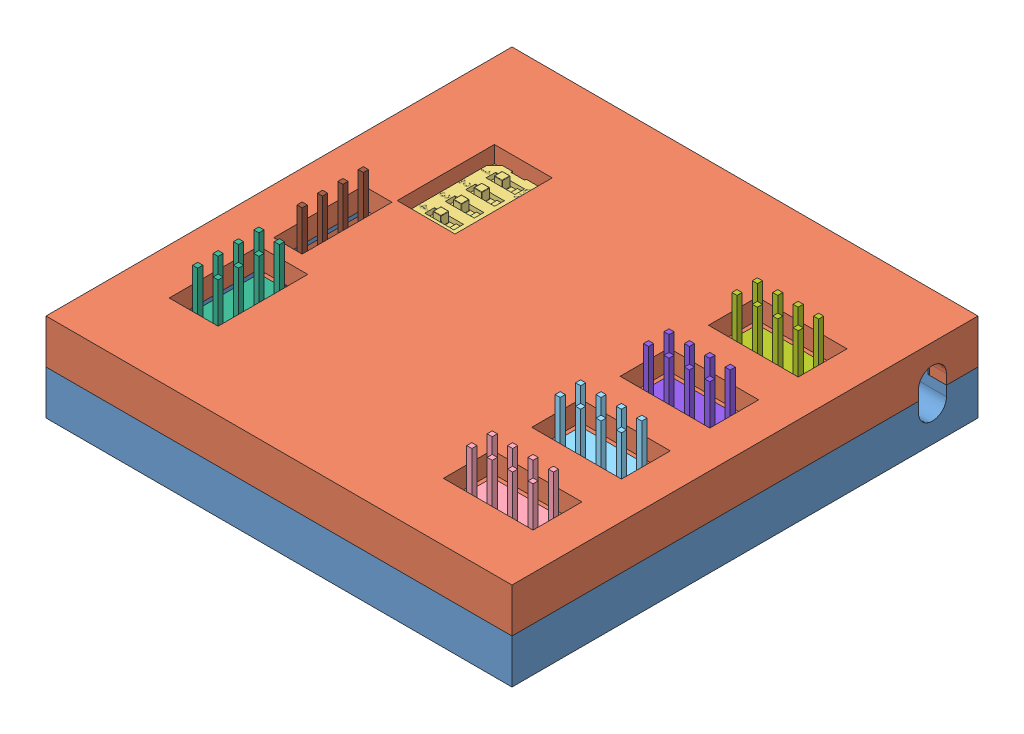
SolidWorks assembly batman, configuration 默认. Lengths in mm.
Overall size (58 14.53 58).
199 component instances, 74 part files, 6 mates.
Components (placement in the parent):
- base-2: base [默认] at (12.8694 5.5 -3.2255) size (58 8.5 58)
- PCB1-1: PCB1 [默认] at (-12.1306 5.9914 21.7745) x (1 0 0) z (0 1 0) size (50 50 11.54)
  - PCB1(2)^PCB1-1: PCB1(2)^PCB1 [默认] at origin size (50 50 11.54) (virtual)
    - Boardbat^PCB1(2)_PCB1-1: Boardbat^PCB1(2)_PCB1 [默认] at origin size (50 50 1.69) (virtual)
      - Open CASCADE STEP translator 6.8 2.1.1^Boardbat_PCB1(2)_PCB1-1: Open CASCADE STEP translator 6.8 2.1.1^Boardbat_PCB1(2)_PCB1 [默认] at (0 0 -1.6914) size (50 50 1.69) (virtual)
    - S1bat^PCB1(2)_PCB1-1: S1bat^PCB1(2)_PCB1 [默认] at origin size (9.8 11.1 4.34) (virtual)
      - SMD_DIP_SWITCH_4P^S1bat_PCB1(2)_PCB1-1: SMD_DIP_SWITCH_4P^S1bat_PCB1(2)_PCB1 [默认] at (9.0244 36.3424 0) x (0 -1 0) z (0 0 1) size (11.1 9.8 4.34) (virtual)
    - P6bat^PCB1(2)_PCB1-1: P6bat^PCB1(2)_PCB1 [默认] at origin size (10.16 5.08 11.54) (virtual)
      - HDR2x4^P6bat_PCB1(2)_PCB1-1: HDR2x4^P6bat_PCB1(2)_PCB1 [默认] at (40.0001 7.5401 0) x (1 0 0) z (0 0 1) size (10.16 5.08 11.54) (virtual)
    - P5bat^PCB1(2)_PCB1-1: P5bat^PCB1(2)_PCB1 [默认] at origin size (10.16 5.08 11.54) (virtual)
      - HDR2x4^P5bat_PCB1(2)_PCB1-1: HDR2x4^P5bat_PCB1(2)_PCB1 [默认] at (40.0001 18.5401 0) x (1 0 0) z (0 0 1) size (10.16 5.08 11.54) (virtual)
    - P4bat^PCB1(2)_PCB1-1: P4bat^PCB1(2)_PCB1 [默认] at origin size (5.08 10.16 11.54) (virtual)
      - HDR2x4^P4bat_PCB1(2)_PCB1-1: HDR2x4^P4bat_PCB1(2)_PCB1 [默认] at (6.0401 14.9999 0) x (0 -1 0) z (0 0 1) size (10.16 5.08 11.54) (virtual)
    - P3bat^PCB1(2)_PCB1-1: P3bat^PCB1(2)_PCB1 [默认] at origin size (10.16 5.08 11.54) (virtual)
      - HDR2x4^P3bat_PCB1(2)_PCB1-1: HDR2x4^P3bat_PCB1(2)_PCB1 [默认] at (40.0001 40.5401 0) x (1 0 0) z (0 0 1) size (10.16 5.08 11.54) (virtual)
    - P2bat^PCB1(2)_PCB1-1: P2bat^PCB1(2)_PCB1 [默认] at origin size (10.16 5.08 11.54) (virtual)
      - HDR2x4^P2bat_PCB1(2)_PCB1-1: HDR2x4^P2bat_PCB1(2)_PCB1 [默认] at (40.0001 29.5401 0) x (1 0 0) z (0 0 1) size (10.16 5.08 11.54) (virtual)
    - U3bat^PCB1(2)_PCB1-1: U3bat^PCB1(2)_PCB1 [默认] at origin size (2.8 2.9 1.45) (virtual)
      - 6249525824^U3bat_PCB1(2)_PCB1-1: 6249525824^U3bat_PCB1(2)_PCB1 [默认] at (16.256 4.064 0) x (-1 0 0) z (0 0 1) size (2.8 2.9 1.45) (virtual)
        - Body^6249525824_U3bat_PCB1(2)_PCB1-1: Body^6249525824_U3bat_PCB1(2)_PCB1 [默认] at origin size (1.6 2.9 1.38) (virtual)
        - PinsArrayLR^6249525824_U3bat_PCB1(2)_PCB1-1: PinsArrayLR^6249525824_U3bat_PCB1(2)_PCB1 [默认] at origin size (2.8 2.3 0.75) (virtual)
    - U2bat^PCB1(2)_PCB1-1: U2bat^PCB1(2)_PCB1 [默认] at origin size (2.9 2.8 1) (virtual)
      - 6249527824^U2bat_PCB1(2)_PCB1-1: 6249527824^U2bat_PCB1(2)_PCB1 [默认] at (22.987 15.509 0) x (0 -1 0) z (-1 0 0) size (2.8 1 2.9) (virtual)
    - U1bat^PCB1(2)_PCB1-1: U1bat^PCB1(2)_PCB1 [默认] at origin size (2.9 2.8 1) (virtual)
      - 6249527824^U1bat_PCB1(2)_PCB1-1: 6249527824^U1bat_PCB1(2)_PCB1 [默认] at (25.527 40.075 0) x (0 -1 0) z (-1 0 0) size (2.8 1 2.9) (virtual)
    - R15bat^PCB1(2)_PCB1-1: R15bat^PCB1(2)_PCB1 [默认] at origin size (1.6 0.8 0.45) (virtual)
      - R0603^R15bat_PCB1(2)_PCB1-1: R0603^R15bat_PCB1(2)_PCB1 [默认] at (21.7171 8.6361 0) x (1 0 0) z (0 0 1) size (1.6 0.8 0.45) (virtual)
    - R14bat^PCB1(2)_PCB1-1: R14bat^PCB1(2)_PCB1 [默认] at origin size (3.46 3.05 1.58) (virtual)
      - 6249526064^R14bat_PCB1(2)_PCB1-1: 6249526064^R14bat_PCB1(2)_PCB1 [默认] at (29.718 7.62 4.4704) x (0 -1 0) z (0 0 -1) size (3.05 3.46 1.58) (virtual)
        - pot1.1^6249526064_R14bat_PCB1(2)_PCB1-1: pot1.1^6249526064_R14bat_PCB1(2)_PCB1 [默认] at (-1.7102 -1.6618 3.4563) size (3 3.46 1.06) (virtual)
        - pot.2^6249526064_R14bat_PCB1(2)_PCB1-1: pot.2^6249526064_R14bat_PCB1(2)_PCB1 [默认] at (-0.2427 -0.0677 2.935) x (-0.009438 0.999936 -0.006241) z (-0.002294 0.00622 0.999978) size (3.06 3 0.7) (virtual)
    - R13bat^PCB1(2)_PCB1-1: R13bat^PCB1(2)_PCB1 [默认] at origin size (0.8 1.6 0.45) (virtual)
      - R0603^R13bat_PCB1(2)_PCB1-1: R0603^R13bat_PCB1(2)_PCB1 [默认] at (15.1131 8.3819 0) x (0 -1 0) z (0 0 1) size (1.6 0.8 0.45) (virtual)
    - R12bat^PCB1(2)_PCB1-1: R12bat^PCB1(2)_PCB1 [默认] at origin size (1.6 0.8 0.45) (virtual)
      - R0603^R12bat_PCB1(2)_PCB1-1: R0603^R12bat_PCB1(2)_PCB1 [默认] at (42.0369 2.4131 -1.6914) x (-1 0 0) z (0 0 -1) size (1.6 0.8 0.45) (virtual)
    - R11bat^PCB1(2)_PCB1-1: R11bat^PCB1(2)_PCB1 [默认] at origin size (0.8 1.6 0.45) (virtual)
      - R0603^R11bat_PCB1(2)_PCB1-1: R0603^R11bat_PCB1(2)_PCB1 [默认] at (33.9091 7.7469 0) x (0 -1 0) z (0 0 1) size (1.6 0.8 0.45) (virtual)
    - R10bat^PCB1(2)_PCB1-1: R10bat^PCB1(2)_PCB1 [默认] at origin size (1.6 0.8 0.45) (virtual)
      - R0603^R10bat_PCB1(2)_PCB1-1: R0603^R10bat_PCB1(2)_PCB1 [默认] at (18.6689 16.1289 0) x (-1 0 0) z (0 0 1) size (1.6 0.8 0.45) (virtual)
    - R9bat^PCB1(2)_PCB1-1: R9bat^PCB1(2)_PCB1 [默认] at origin size (1.6 0.8 0.45) (virtual)
      - R0603^R9bat_PCB1(2)_PCB1-1: R0603^R9bat_PCB1(2)_PCB1 [默认] at (42.0369 13.4621 -1.6914) x (-1 0 0) z (0 0 -1) size (1.6 0.8 0.45) (virtual)
    - R8bat^PCB1(2)_PCB1-1: R8bat^PCB1(2)_PCB1 [默认] at origin size (1.6 0.8 0.45) (virtual)
      - R0603^R8bat_PCB1(2)_PCB1-1: R0603^R8bat_PCB1(2)_PCB1 [默认] at (27.4321 13.8431 0) x (1 0 0) z (0 0 1) size (1.6 0.8 0.45) (virtual)
    - R7bat^PCB1(2)_PCB1-1: R7bat^PCB1(2)_PCB1 [默认] at origin size (1.6 0.8 0.45) (virtual)
      - R0603^R7bat_PCB1(2)_PCB1-1: R0603^R7bat_PCB1(2)_PCB1 [默认] at (18.6689 13.9699 0) x (-1 0 0) z (0 0 1) size (1.6 0.8 0.45) (virtual)
    - R6bat^PCB1(2)_PCB1-1: R6bat^PCB1(2)_PCB1 [默认] at origin size (0.8 1.6 0.45) (virtual)
      - R0603^R6bat_PCB1(2)_PCB1-1: R0603^R6bat_PCB1(2)_PCB1 [默认] at (17.6531 19.5579 0) x (0 -1 0) z (0 0 1) size (1.6 0.8 0.45) (virtual)
    - R5bat^PCB1(2)_PCB1-1: R5bat^PCB1(2)_PCB1 [默认] at origin size (1.6 0.8 0.45) (virtual)
      - R0603^R5bat_PCB1(2)_PCB1-1: R0603^R5bat_PCB1(2)_PCB1 [默认] at (42.0371 24.3839 -1.6914) x (1 0 0) z (0 0 -1) size (1.6 0.8 0.45) (virtual)
    - R4bat^PCB1(2)_PCB1-1: R4bat^PCB1(2)_PCB1 [默认] at origin size (0.8 1.6 0.45) (virtual)
      - R0603^R4bat_PCB1(2)_PCB1-1: R0603^R4bat_PCB1(2)_PCB1 [默认] at (21.5899 39.1161 0) x (0 1 0) z (0 0 1) size (1.6 0.8 0.45) (virtual)
    - R3bat^PCB1(2)_PCB1-1: R3bat^PCB1(2)_PCB1 [默认] at origin size (1.6 0.8 0.45) (virtual)
      - R0603^R3bat_PCB1(2)_PCB1-1: R0603^R3bat_PCB1(2)_PCB1 [默认] at (41.9099 35.4331 -1.6914) x (-1 0 0) z (0 0 -1) size (1.6 0.8 0.45) (virtual)
    - R2bat^PCB1(2)_PCB1-1: R2bat^PCB1(2)_PCB1 [默认] at origin size (1.6 0.8 0.45) (virtual)
      - R0603^R2bat_PCB1(2)_PCB1-1: R0603^R2bat_PCB1(2)_PCB1 [默认] at (29.7181 38.7351 0) x (1 0 0) z (0 0 1) size (1.6 0.8 0.45) (virtual)
    - R1bat^PCB1(2)_PCB1-1: R1bat^PCB1(2)_PCB1 [默认] at origin size (0.8 1.6 0.45) (virtual)
      - R0603^R1bat_PCB1(2)_PCB1-1: R0603^R1bat_PCB1(2)_PCB1 [默认] at (21.7171 44.4499 0) x (0 -1 0) z (0 0 1) size (1.6 0.8 0.45) (virtual)
    - P1bat^PCB1(2)_PCB1-1: P1bat^PCB1(2)_PCB1 [默认] at origin size (2.54 10.16 11.54) (virtual)
      - 1001-4^P1bat_PCB1(2)_PCB1-1: 1001-4^P1bat_PCB1(2)_PCB1 [默认] at (3.5001 27.9999 0) x (0 -1 0) z (0 0 1) size (10.16 2.54 11.54) (virtual)
    - LED4bat^PCB1(2)_PCB1-1: LED4bat^PCB1(2)_PCB1 [默认] at origin size (1.8 0.9 0.8) (virtual)
      - LEDC0603^LED4bat_PCB1(2)_PCB1-1: LEDC0603^LED4bat_PCB1(2)_PCB1 [默认] at (43.9422 2.4131 0) x (1 0 0) z (0 0 1) size (1.8 0.9 0.8) (virtual)
    - LED3bat^PCB1(2)_PCB1-1: LED3bat^PCB1(2)_PCB1 [默认] at origin size (1.8 0.9 0.8) (virtual)
      - LEDC0603^LED3bat_PCB1(2)_PCB1-1: LEDC0603^LED3bat_PCB1(2)_PCB1 [默认] at (43.9422 13.4621 0) x (1 0 0) z (0 0 1) size (1.8 0.9 0.8) (virtual)
    - LED2bat^PCB1(2)_PCB1-1: LED2bat^PCB1(2)_PCB1 [默认] at origin size (1.8 0.9 0.8) (virtual)
      - LEDC0603^LED2bat_PCB1(2)_PCB1-1: LEDC0603^LED2bat_PCB1(2)_PCB1 [默认] at (43.8152 35.4331 0) x (1 0 0) z (0 0 1) size (1.8 0.9 0.8) (virtual)
    - LED1bat^PCB1(2)_PCB1-1: LED1bat^PCB1(2)_PCB1 [默认] at origin size (1.8 0.9 0.8) (virtual)
      - LEDC0603^LED1bat_PCB1(2)_PCB1-1: LEDC0603^LED1bat_PCB1(2)_PCB1 [默认] at (43.9422 24.3841 0) x (1 0 0) z (0 0 1) size (1.8 0.9 0.8) (virtual)
    - L3bat^PCB1(2)_PCB1-1: L3bat^PCB1(2)_PCB1 [默认] at origin size (4.2 4.7 1.85) (virtual)
      - CSAB0420^L3bat_PCB1(2)_PCB1-1: CSAB0420^L3bat_PCB1(2)_PCB1 [默认] at (22.479 3.5744 0.05) x (1 0 0) z (0 0 1) size (4.2 4.7 1.85) (virtual)
        - CSAB0420-0^CSAB0420_L3bat_PCB1(2)_PCB1-1: CSAB0420-0^CSAB0420_L3bat_PCB1(2)_PCB1 [默认] x (1 0 0) z (0 0 -1) size (4.2 4.2 1.8) (virtual)
        - 0420____^CSAB0420_L3bat_PCB1(2)_PCB1-1: 0420____^CSAB0420_L3bat_PCB1(2)_PCB1 [默认] at (0 -2.1 0.425) x (1 0 0) z (0 -1 0) size (2 1.2 0.95) (virtual)
        - 0420____^CSAB0420_L3bat_PCB1(2)_PCB1-2: 0420____^CSAB0420_L3bat_PCB1(2)_PCB1 [默认] at (0 2.1 0.425) x (-1 0 0) z (0 1 0) size (2 1.2 0.95) (virtual)
    - L2bat^PCB1(2)_PCB1-1: L2bat^PCB1(2)_PCB1 [默认] at origin size (4.2 4.7 1.85) (virtual)
      - CSAB0420^L2bat_PCB1(2)_PCB1-1: CSAB0420^L2bat_PCB1(2)_PCB1 [默认] at (30.353 19.9206 0.05) x (-1 0 0) z (0 0 1) size (4.2 4.7 1.85) (virtual)
        - CSAB0420-0^CSAB0420_L2bat_PCB1(2)_PCB1-1: CSAB0420-0^CSAB0420_L2bat_PCB1(2)_PCB1 [默认] x (1 0 0) z (0 0 -1) size (4.2 4.2 1.8) (virtual)
        - 0420____^CSAB0420_L2bat_PCB1(2)_PCB1-1: 0420____^CSAB0420_L2bat_PCB1(2)_PCB1 [默认] at (0 -2.1 0.425) x (1 0 0) z (0 -1 0) size (2 1.2 0.95) (virtual)
        - 0420____^CSAB0420_L2bat_PCB1(2)_PCB1-2: 0420____^CSAB0420_L2bat_PCB1(2)_PCB1 [默认] at (0 2.1 0.425) x (-1 0 0) z (0 1 0) size (2 1.2 0.95) (virtual)
    - L1bat^PCB1(2)_PCB1-1: L1bat^PCB1(2)_PCB1 [默认] at origin size (4.2 4.7 1.85) (virtual)
      - CSAB0420^L1bat_PCB1(2)_PCB1-1: CSAB0420^L1bat_PCB1(2)_PCB1 [默认] at (33.655 44.5586 0.05) x (-1 0 0) z (0 0 1) size (4.2 4.7 1.85) (virtual)
        - CSAB0420-0^CSAB0420_L1bat_PCB1(2)_PCB1-1: CSAB0420-0^CSAB0420_L1bat_PCB1(2)_PCB1 [默认] x (1 0 0) z (0 0 -1) size (4.2 4.2 1.8) (virtual)
        - 0420____^CSAB0420_L1bat_PCB1(2)_PCB1-1: 0420____^CSAB0420_L1bat_PCB1(2)_PCB1 [默认] at (0 -2.1 0.425) x (1 0 0) z (0 -1 0) size (2 1.2 0.95) (virtual)
        - 0420____^CSAB0420_L1bat_PCB1(2)_PCB1-2: 0420____^CSAB0420_L1bat_PCB1(2)_PCB1 [默认] at (0 2.1 0.425) x (-1 0 0) z (0 1 0) size (2 1.2 0.95) (virtual)
    - IC1bat^PCB1(2)_PCB1-1: IC1bat^PCB1(2)_PCB1 [默认] at origin size (6.71 6.3 1.8) (virtual)
      - 6249526864^IC1bat_PCB1(2)_PCB1-1: 6249526864^IC1bat_PCB1(2)_PCB1 [默认] at (24.257 29.845 1.22) x (0 1 0) z (1 0 0) size (6.3 1.8 6.71) (virtual)
    - D1bat^PCB1(2)_PCB1-1: D1bat^PCB1(2)_PCB1 [默认] at origin size (5.81 2.92 2.3) (virtual)
      - SMA(DO-214AC)^D1bat_PCB1(2)_PCB1-1: SMA(DO-214AC)^D1bat_PCB1(2)_PCB1 [默认] at (30.2261 3.0481 0) x (1 0 0) z (0 0 1) size (5.81 2.92 2.3) (virtual)
    - C16bat^PCB1(2)_PCB1-1: C16bat^PCB1(2)_PCB1 [默认] at origin size (0.95 1.75 0.85) (virtual)
      - 6351899600^C16bat_PCB1(2)_PCB1-1: 6351899600^C16bat_PCB1(2)_PCB1 [默认] at (17.145 8.382 0) size (0.95 1.05 0.85) (virtual)
        - Extruded^6351899600_C16bat_PCB1(2)_PCB1-1: Extruded^6351899600_C16bat_PCB1(2)_PCB1 [默认] at origin size (0.95 1.05 0.85) (virtual)
      - 6351899200^C16bat_PCB1(2)_PCB1-1: 6351899200^C16bat_PCB1(2)_PCB1 [默认] at (17.145 9.082 0) size (0.95 0.35 0.85) (virtual)
        - Extruded-1^6351899200_C16bat_PCB1(2)_PCB1-1: Extruded-1^6351899200_C16bat_PCB1(2)_PCB1 [默认] at origin size (0.95 0.35 0.85) (virtual)
      - 6351899200^C16bat_PCB1(2)_PCB1-2: 6351899200^C16bat_PCB1(2)_PCB1 [默认] at (17.145 7.682 0) size (0.95 0.35 0.85) (virtual)
        - Extruded-1^6351899200_C16bat_PCB1(2)_PCB1-1: Extruded-1^6351899200_C16bat_PCB1(2)_PCB1 [默认] at origin size (0.95 0.35 0.85) (virtual)
    - C15bat^PCB1(2)_PCB1-1: C15bat^PCB1(2)_PCB1 [默认] at origin size (0.95 1.75 0.85) (virtual)
      - 6351899200^C15bat_PCB1(2)_PCB1-1: 6351899200^C15bat_PCB1(2)_PCB1 [默认] at (35.941 4.764 0) size (0.95 0.35 0.85) (virtual)
        - Extruded-1^6351899200_C15bat_PCB1(2)_PCB1-1: Extruded-1^6351899200_C15bat_PCB1(2)_PCB1 [默认] at origin size (0.95 0.35 0.85) (virtual)
      - 6351899200^C15bat_PCB1(2)_PCB1-2: 6351899200^C15bat_PCB1(2)_PCB1 [默认] at (35.941 3.364 0) size (0.95 0.35 0.85) (virtual)
        - Extruded-1^6351899200_C15bat_PCB1(2)_PCB1-1: Extruded-1^6351899200_C15bat_PCB1(2)_PCB1 [默认] at origin size (0.95 0.35 0.85) (virtual)
      - 6351899600^C15bat_PCB1(2)_PCB1-1: 6351899600^C15bat_PCB1(2)_PCB1 [默认] at (35.941 4.064 0) size (0.95 1.05 0.85) (virtual)
        - Extruded^6351899600_C15bat_PCB1(2)_PCB1-1: Extruded^6351899600_C15bat_PCB1(2)_PCB1 [默认] at origin size (0.95 1.05 0.85) (virtual)
    - C14bat^PCB1(2)_PCB1-1: C14bat^PCB1(2)_PCB1 [默认] at origin size (1.75 0.95 0.85) (virtual)
      - 6351616128^C14bat_PCB1(2)_PCB1-1: 6351616128^C14bat_PCB1(2)_PCB1 [默认] at (31.496 13.843 0) size (1.05 0.95 0.85) (virtual)
        - Extruded-2^6351616128_C14bat_PCB1(2)_PCB1-1: Extruded-2^6351616128_C14bat_PCB1(2)_PCB1 [默认] at origin size (1.05 0.95 0.85) (virtual)
      - 6351615888^C14bat_PCB1(2)_PCB1-1: 6351615888^C14bat_PCB1(2)_PCB1 [默认] at (32.196 13.843 0) size (0.35 0.95 0.85) (virtual)
        - Extruded-3^6351615888_C14bat_PCB1(2)_PCB1-1: Extruded-3^6351615888_C14bat_PCB1(2)_PCB1 [默认] at origin size (0.35 0.95 0.85) (virtual)
      - 6351615888^C14bat_PCB1(2)_PCB1-2: 6351615888^C14bat_PCB1(2)_PCB1 [默认] at (30.796 13.843 0) size (0.35 0.95 0.85) (virtual)
        - Extruded-3^6351615888_C14bat_PCB1(2)_PCB1-1: Extruded-3^6351615888_C14bat_PCB1(2)_PCB1 [默认] at origin size (0.35 0.95 0.85) (virtual)
    - C13bat^PCB1(2)_PCB1-1: C13bat^PCB1(2)_PCB1 [默认] at origin size (1.75 0.95 0.85) (virtual)
      - 6351616128^C13bat_PCB1(2)_PCB1-1: 6351616128^C13bat_PCB1(2)_PCB1 [默认] at (31.496 15.875 0) size (1.05 0.95 0.85) (virtual)
        - Extruded-2^6351616128_C13bat_PCB1(2)_PCB1-1: Extruded-2^6351616128_C13bat_PCB1(2)_PCB1 [默认] at origin size (1.05 0.95 0.85) (virtual)
      - 6351615888^C13bat_PCB1(2)_PCB1-1: 6351615888^C13bat_PCB1(2)_PCB1 [默认] at (32.196 15.875 0) size (0.35 0.95 0.85) (virtual)
        - Extruded-3^6351615888_C13bat_PCB1(2)_PCB1-1: Extruded-3^6351615888_C13bat_PCB1(2)_PCB1 [默认] at origin size (0.35 0.95 0.85) (virtual)
      - 6351615888^C13bat_PCB1(2)_PCB1-2: 6351615888^C13bat_PCB1(2)_PCB1 [默认] at (30.796 15.875 0) size (0.35 0.95 0.85) (virtual)
        - Extruded-3^6351615888_C13bat_PCB1(2)_PCB1-1: Extruded-3^6351615888_C13bat_PCB1(2)_PCB1 [默认] at origin size (0.35 0.95 0.85) (virtual)
    - C12bat^PCB1(2)_PCB1-1: C12bat^PCB1(2)_PCB1 [默认] at origin size (1.75 0.95 0.85) (virtual)
      - 6351616128^C12bat_PCB1(2)_PCB1-1: 6351616128^C12bat_PCB1(2)_PCB1 [默认] at (22.86 19.939 0) size (1.05 0.95 0.85) (virtual)
        - Extruded-2^6351616128_C12bat_PCB1(2)_PCB1-1: Extruded-2^6351616128_C12bat_PCB1(2)_PCB1 [默认] at origin size (1.05 0.95 0.85) (virtual)
      - 6351615888^C12bat_PCB1(2)_PCB1-1: 6351615888^C12bat_PCB1(2)_PCB1 [默认] at (22.16 19.939 0) size (0.35 0.95 0.85) (virtual)
        - Extruded-3^6351615888_C12bat_PCB1(2)_PCB1-1: Extruded-3^6351615888_C12bat_PCB1(2)_PCB1 [默认] at origin size (0.35 0.95 0.85) (virtual)
      - 6351615888^C12bat_PCB1(2)_PCB1-2: 6351615888^C12bat_PCB1(2)_PCB1 [默认] at (23.56 19.939 0) size (0.35 0.95 0.85) (virtual)
        - Extruded-3^6351615888_C12bat_PCB1(2)_PCB1-1: Extruded-3^6351615888_C12bat_PCB1(2)_PCB1 [默认] at origin size (0.35 0.95 0.85) (virtual)
    - C11bat^PCB1(2)_PCB1-1: C11bat^PCB1(2)_PCB1 [默认] at origin size (1.75 0.95 0.85) (virtual)
      - 6351616128^C11bat_PCB1(2)_PCB1-1: 6351616128^C11bat_PCB1(2)_PCB1 [默认] at (22.86 21.844 0) size (1.05 0.95 0.85) (virtual)
        - Extruded-2^6351616128_C11bat_PCB1(2)_PCB1-1: Extruded-2^6351616128_C11bat_PCB1(2)_PCB1 [默认] at origin size (1.05 0.95 0.85) (virtual)
      - 6351615888^C11bat_PCB1(2)_PCB1-1: 6351615888^C11bat_PCB1(2)_PCB1 [默认] at (22.16 21.844 0) size (0.35 0.95 0.85) (virtual)
        - Extruded-3^6351615888_C11bat_PCB1(2)_PCB1-1: Extruded-3^6351615888_C11bat_PCB1(2)_PCB1 [默认] at origin size (0.35 0.95 0.85) (virtual)
      - 6351615888^C11bat_PCB1(2)_PCB1-2: 6351615888^C11bat_PCB1(2)_PCB1 [默认] at (23.56 21.844 0) size (0.35 0.95 0.85) (virtual)
        - Extruded-3^6351615888_C11bat_PCB1(2)_PCB1-1: Extruded-3^6351615888_C11bat_PCB1(2)_PCB1 [默认] at origin size (0.35 0.95 0.85) (virtual)
    - C10bat^PCB1(2)_PCB1-1: C10bat^PCB1(2)_PCB1 [默认] at origin size (0.95 1.75 0.85) (virtual)
      - 6351899200^C10bat_PCB1(2)_PCB1-1: 6351899200^C10bat_PCB1(2)_PCB1 [默认] at (26.289 18.353 0) size (0.95 0.35 0.85) (virtual)
        - Extruded-1^6351899200_C10bat_PCB1(2)_PCB1-1: Extruded-1^6351899200_C10bat_PCB1(2)_PCB1 [默认] at origin size (0.95 0.35 0.85) (virtual)
      - 6351899200^C10bat_PCB1(2)_PCB1-2: 6351899200^C10bat_PCB1(2)_PCB1 [默认] at (26.289 16.953 0) size (0.95 0.35 0.85) (virtual)
        - Extruded-1^6351899200_C10bat_PCB1(2)_PCB1-1: Extruded-1^6351899200_C10bat_PCB1(2)_PCB1 [默认] at origin size (0.95 0.35 0.85) (virtual)
      - 6351899600^C10bat_PCB1(2)_PCB1-1: 6351899600^C10bat_PCB1(2)_PCB1 [默认] at (26.289 17.653 0) size (0.95 1.05 0.85) (virtual)
        - Extruded^6351899600_C10bat_PCB1(2)_PCB1-1: Extruded^6351899600_C10bat_PCB1(2)_PCB1 [默认] at origin size (0.95 1.05 0.85) (virtual)
    - C9bat^PCB1(2)_PCB1-1: C9bat^PCB1(2)_PCB1 [默认] at origin size (0.95 1.75 0.85) (virtual)
      - 6351899600^C9bat_PCB1(2)_PCB1-1: 6351899600^C9bat_PCB1(2)_PCB1 [默认] at (33.02 32.315 0) size (0.95 1.05 0.85) (virtual)
        - Extruded^6351899600_C9bat_PCB1(2)_PCB1-1: Extruded^6351899600_C9bat_PCB1(2)_PCB1 [默认] at origin size (0.95 1.05 0.85) (virtual)
      - 6351899200^C9bat_PCB1(2)_PCB1-1: 6351899200^C9bat_PCB1(2)_PCB1 [默认] at (33.02 31.615 0) size (0.95 0.35 0.85) (virtual)
        - Extruded-1^6351899200_C9bat_PCB1(2)_PCB1-1: Extruded-1^6351899200_C9bat_PCB1(2)_PCB1 [默认] at origin size (0.95 0.35 0.85) (virtual)
      - 6351899200^C9bat_PCB1(2)_PCB1-2: 6351899200^C9bat_PCB1(2)_PCB1 [默认] at (33.02 33.015 0) size (0.95 0.35 0.85) (virtual)
        - Extruded-1^6351899200_C9bat_PCB1(2)_PCB1-1: Extruded-1^6351899200_C9bat_PCB1(2)_PCB1 [默认] at origin size (0.95 0.35 0.85) (virtual)
    - C8bat^PCB1(2)_PCB1-1: C8bat^PCB1(2)_PCB1 [默认] at origin size (0.95 1.75 0.85) (virtual)
      - 6351899600^C8bat_PCB1(2)_PCB1-1: 6351899600^C8bat_PCB1(2)_PCB1 [默认] at (30.734 32.315 0) size (0.95 1.05 0.85) (virtual)
        - Extruded^6351899600_C8bat_PCB1(2)_PCB1-1: Extruded^6351899600_C8bat_PCB1(2)_PCB1 [默认] at origin size (0.95 1.05 0.85) (virtual)
      - 6351899200^C8bat_PCB1(2)_PCB1-1: 6351899200^C8bat_PCB1(2)_PCB1 [默认] at (30.734 31.615 0) size (0.95 0.35 0.85) (virtual)
        - Extruded-1^6351899200_C8bat_PCB1(2)_PCB1-1: Extruded-1^6351899200_C8bat_PCB1(2)_PCB1 [默认] at origin size (0.95 0.35 0.85) (virtual)
      - 6351899200^C8bat_PCB1(2)_PCB1-2: 6351899200^C8bat_PCB1(2)_PCB1 [默认] at (30.734 33.015 0) size (0.95 0.35 0.85) (virtual)
        - Extruded-1^6351899200_C8bat_PCB1(2)_PCB1-1: Extruded-1^6351899200_C8bat_PCB1(2)_PCB1 [默认] at origin size (0.95 0.35 0.85) (virtual)
    - C7bat^PCB1(2)_PCB1-1: C7bat^PCB1(2)_PCB1 [默认] at origin size (0.95 1.75 0.85) (virtual)
      - 6351899200^C7bat_PCB1(2)_PCB1-1: 6351899200^C7bat_PCB1(2)_PCB1 [默认] at (30.861 28.062 0) size (0.95 0.35 0.85) (virtual)
        - Extruded-1^6351899200_C7bat_PCB1(2)_PCB1-1: Extruded-1^6351899200_C7bat_PCB1(2)_PCB1 [默认] at origin size (0.95 0.35 0.85) (virtual)
      - 6351899200^C7bat_PCB1(2)_PCB1-2: 6351899200^C7bat_PCB1(2)_PCB1 [默认] at (30.861 26.662 0) size (0.95 0.35 0.85) (virtual)
        - Extruded-1^6351899200_C7bat_PCB1(2)_PCB1-1: Extruded-1^6351899200_C7bat_PCB1(2)_PCB1 [默认] at origin size (0.95 0.35 0.85) (virtual)
      - 6351899600^C7bat_PCB1(2)_PCB1-1: 6351899600^C7bat_PCB1(2)_PCB1 [默认] at (30.861 27.362 0) size (0.95 1.05 0.85) (virtual)
        - Extruded^6351899600_C7bat_PCB1(2)_PCB1-1: Extruded^6351899600_C7bat_PCB1(2)_PCB1 [默认] at origin size (0.95 1.05 0.85) (virtual)
    - C6bat^PCB1(2)_PCB1-1: C6bat^PCB1(2)_PCB1 [默认] at origin size (0.95 1.75 0.85) (virtual)
      - 6351899200^C6bat_PCB1(2)_PCB1-1: 6351899200^C6bat_PCB1(2)_PCB1 [默认] at (33.02 28.189 0) size (0.95 0.35 0.85) (virtual)
        - Extruded-1^6351899200_C6bat_PCB1(2)_PCB1-1: Extruded-1^6351899200_C6bat_PCB1(2)_PCB1 [默认] at origin size (0.95 0.35 0.85) (virtual)
      - 6351899200^C6bat_PCB1(2)_PCB1-2: 6351899200^C6bat_PCB1(2)_PCB1 [默认] at (33.02 26.789 0) size (0.95 0.35 0.85) (virtual)
        - Extruded-1^6351899200_C6bat_PCB1(2)_PCB1-1: Extruded-1^6351899200_C6bat_PCB1(2)_PCB1 [默认] at origin size (0.95 0.35 0.85) (virtual)
      - 6351899600^C6bat_PCB1(2)_PCB1-1: 6351899600^C6bat_PCB1(2)_PCB1 [默认] at (33.02 27.489 0) size (0.95 1.05 0.85) (virtual)
        - Extruded^6351899600_C6bat_PCB1(2)_PCB1-1: Extruded^6351899600_C6bat_PCB1(2)_PCB1 [默认] at origin size (0.95 1.05 0.85) (virtual)
    - C5bat^PCB1(2)_PCB1-1: C5bat^PCB1(2)_PCB1 [默认] at origin size (1.75 0.95 0.85) (virtual)
      - 6351616128^C5bat_PCB1(2)_PCB1-1: 6351616128^C5bat_PCB1(2)_PCB1 [默认] at (33.44 40.513 0) size (1.05 0.95 0.85) (virtual)
        - Extruded-2^6351616128_C5bat_PCB1(2)_PCB1-1: Extruded-2^6351616128_C5bat_PCB1(2)_PCB1 [默认] at origin size (1.05 0.95 0.85) (virtual)
      - 6351615888^C5bat_PCB1(2)_PCB1-1: 6351615888^C5bat_PCB1(2)_PCB1 [默认] at (34.14 40.513 0) size (0.35 0.95 0.85) (virtual)
        - Extruded-3^6351615888_C5bat_PCB1(2)_PCB1-1: Extruded-3^6351615888_C5bat_PCB1(2)_PCB1 [默认] at origin size (0.35 0.95 0.85) (virtual)
      - 6351615888^C5bat_PCB1(2)_PCB1-2: 6351615888^C5bat_PCB1(2)_PCB1 [默认] at (32.74 40.513 0) size (0.35 0.95 0.85) (virtual)
        - Extruded-3^6351615888_C5bat_PCB1(2)_PCB1-1: Extruded-3^6351615888_C5bat_PCB1(2)_PCB1 [默认] at origin size (0.35 0.95 0.85) (virtual)
    - C4bat^PCB1(2)_PCB1-1: C4bat^PCB1(2)_PCB1 [默认] at origin size (1.75 0.95 0.85) (virtual)
      - 6351616128^C4bat_PCB1(2)_PCB1-1: 6351616128^C4bat_PCB1(2)_PCB1 [默认] at (33.44 38.735 0) size (1.05 0.95 0.85) (virtual)
        - Extruded-2^6351616128_C4bat_PCB1(2)_PCB1-1: Extruded-2^6351616128_C4bat_PCB1(2)_PCB1 [默认] at origin size (1.05 0.95 0.85) (virtual)
      - 6351615888^C4bat_PCB1(2)_PCB1-1: 6351615888^C4bat_PCB1(2)_PCB1 [默认] at (34.14 38.735 0) size (0.35 0.95 0.85) (virtual)
        - Extruded-3^6351615888_C4bat_PCB1(2)_PCB1-1: Extruded-3^6351615888_C4bat_PCB1(2)_PCB1 [默认] at origin size (0.35 0.95 0.85) (virtual)
      - 6351615888^C4bat_PCB1(2)_PCB1-2: 6351615888^C4bat_PCB1(2)_PCB1 [默认] at (32.74 38.735 0) size (0.35 0.95 0.85) (virtual)
        - Extruded-3^6351615888_C4bat_PCB1(2)_PCB1-1: Extruded-3^6351615888_C4bat_PCB1(2)_PCB1 [默认] at origin size (0.35 0.95 0.85) (virtual)
    - C3bat^PCB1(2)_PCB1-1: C3bat^PCB1(2)_PCB1 [默认] at origin size (1.75 0.95 0.85) (virtual)
      - 6351616128^C3bat_PCB1(2)_PCB1-1: 6351616128^C3bat_PCB1(2)_PCB1 [默认] at (25.4 44.393 0) size (1.05 0.95 0.85) (virtual)
        - Extruded-2^6351616128_C3bat_PCB1(2)_PCB1-1: Extruded-2^6351616128_C3bat_PCB1(2)_PCB1 [默认] at origin size (1.05 0.95 0.85) (virtual)
      - 6351615888^C3bat_PCB1(2)_PCB1-1: 6351615888^C3bat_PCB1(2)_PCB1 [默认] at (24.7 44.393 0) size (0.35 0.95 0.85) (virtual)
        - Extruded-3^6351615888_C3bat_PCB1(2)_PCB1-1: Extruded-3^6351615888_C3bat_PCB1(2)_PCB1 [默认] at origin size (0.35 0.95 0.85) (virtual)
      - 6351615888^C3bat_PCB1(2)_PCB1-2: 6351615888^C3bat_PCB1(2)_PCB1 [默认] at (26.1 44.393 0) size (0.35 0.95 0.85) (virtual)
        - Extruded-3^6351615888_C3bat_PCB1(2)_PCB1-1: Extruded-3^6351615888_C3bat_PCB1(2)_PCB1 [默认] at origin size (0.35 0.95 0.85) (virtual)
    - C2bat^PCB1(2)_PCB1-1: C2bat^PCB1(2)_PCB1 [默认] at origin size (1.75 0.95 0.85) (virtual)
      - 6351616128^C2bat_PCB1(2)_PCB1-1: 6351616128^C2bat_PCB1(2)_PCB1 [默认] at (25.4 46.425 0) size (1.05 0.95 0.85) (virtual)
        - Extruded-2^6351616128_C2bat_PCB1(2)_PCB1-1: Extruded-2^6351616128_C2bat_PCB1(2)_PCB1 [默认] at origin size (1.05 0.95 0.85) (virtual)
      - 6351615888^C2bat_PCB1(2)_PCB1-1: 6351615888^C2bat_PCB1(2)_PCB1 [默认] at (24.7 46.425 0) size (0.35 0.95 0.85) (virtual)
        - Extruded-3^6351615888_C2bat_PCB1(2)_PCB1-1: Extruded-3^6351615888_C2bat_PCB1(2)_PCB1 [默认] at origin size (0.35 0.95 0.85) (virtual)
      - 6351615888^C2bat_PCB1(2)_PCB1-2: 6351615888^C2bat_PCB1(2)_PCB1 [默认] at (26.1 46.425 0) size (0.35 0.95 0.85) (virtual)
        - Extruded-3^6351615888_C2bat_PCB1(2)_PCB1-1: Extruded-3^6351615888_C2bat_PCB1(2)_PCB1 [默认] at origin size (0.35 0.95 0.85) (virtual)
    - C1bat^PCB1(2)_PCB1-1: C1bat^PCB1(2)_PCB1 [默认] at origin size (0.95 1.75 0.85) (virtual)
      - 6351899200^C1bat_PCB1(2)_PCB1-1: 6351899200^C1bat_PCB1(2)_PCB1 [默认] at (29.845 43.626 0) size (0.95 0.35 0.85) (virtual)
        - Extruded-1^6351899200_C1bat_PCB1(2)_PCB1-1: Extruded-1^6351899200_C1bat_PCB1(2)_PCB1 [默认] at origin size (0.95 0.35 0.85) (virtual)
      - 6351899200^C1bat_PCB1(2)_PCB1-2: 6351899200^C1bat_PCB1(2)_PCB1 [默认] at (29.845 42.226 0) size (0.95 0.35 0.85) (virtual)
        - Extruded-1^6351899200_C1bat_PCB1(2)_PCB1-1: Extruded-1^6351899200_C1bat_PCB1(2)_PCB1 [默认] at origin size (0.95 0.35 0.85) (virtual)
      - 6351899600^C1bat_PCB1(2)_PCB1-1: 6351899600^C1bat_PCB1(2)_PCB1 [默认] at (29.845 42.926 0) size (0.95 1.05 0.85) (virtual)
        - Extruded^6351899600_C1bat_PCB1(2)_PCB1-1: Extruded^6351899600_C1bat_PCB1(2)_PCB1 [默认] at origin size (0.95 1.05 0.85) (virtual)
- lid-1: lid [默认] at (12.8694 5.5 -3.2255) size (58 5.5 58)
Mates (geometry in assembly coordinates):
- 同心1: concentric: cylinder of base-2 through (-2.1306 4.3 9.7745) axis (0 -1 0) radius 1.5; cylinder of PCB1-1/PCB1(2)^PCB1-1/Boardbat^PCB1(2)_PCB1-1/Open CASCADE STEP translator 6.8 2.1.1^Boardbat_PCB1(2)_PCB1-1 through (-2.1306 4.3 9.7745) axis (0 -1 0) radius 0.8
- 同心5: concentric: cylinder of base-2 through (-2.1306 4.3 -14.2255) axis (0 -1 0) radius 1.5; cylinder of PCB1-1/PCB1(2)^PCB1-1/Boardbat^PCB1(2)_PCB1-1/Open CASCADE STEP translator 6.8 2.1.1^Boardbat_PCB1(2)_PCB1-1 through (-2.1306 4.3 -14.2255) axis (0 -1 0) radius 0.8
- 重合5: coincident: plane of base-2 through (41.8694 0 -32.2255) normal (1 0 0); plane of lid-1 through (41.8694 0 -32.2255) normal (1 0 0)
- 重合6: coincident: plane of base-2 through (-16.1306 0 -32.2255) normal (0 0 -1); plane of lid-1 through (-16.1306 0 -32.2255) normal (0 0 -1)
- 重合3: coincident: plane of base-2 through (-2.1306 4.3 -14.2255) normal (0 1 0); plane of PCB1-1/PCB1(2)^PCB1-1/Boardbat^PCB1(2)_PCB1-1/Open CASCADE STEP translator 6.8 2.1.1^Boardbat_PCB1(2)_PCB1-1 through (-12.1306 4.3 21.7745) normal (0 -1 0)
- 重合7: coincident: plane of base-2 through (12.8694 5.5 -3.2255) normal (0 1 0); plane of lid-1 through (12.8694 5.5 -3.2255) normal (0 -1 0)
